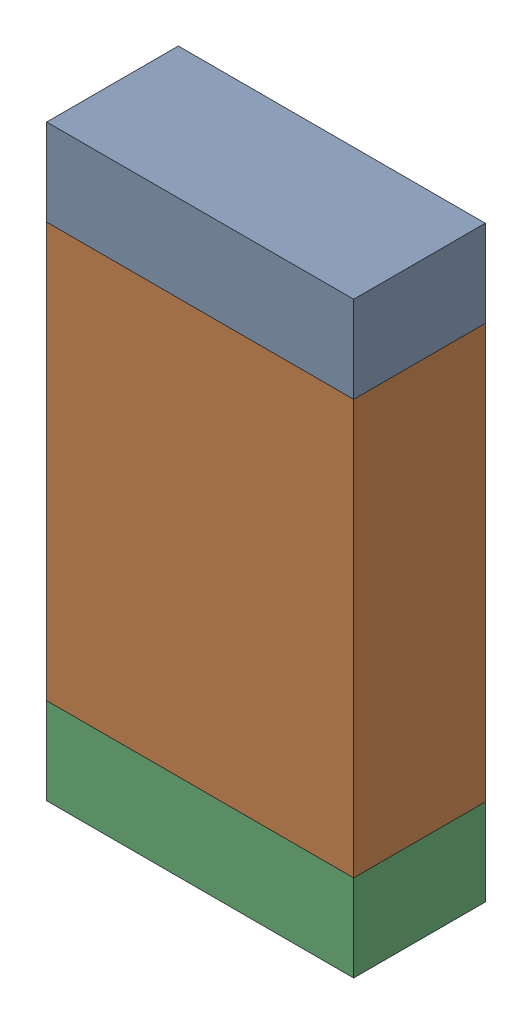
SolidWorks assembly R02, configuration Default. Lengths in mm.
Overall size (1.75 3.35 0.75).
6 component instances, 2 part files, 0 mates.
Components (placement in the parent):
- 959207032-1: 959207032 [Default] at (128.1431 81.3844 0) size (1.75 0.49 0.75)
  - Extruded-4-1: Extruded-4 [Default] at origin size (1.75 0.49 0.75)
- 959207168-1: 959207168 [Default] at (128.1431 79.9569 0) size (1.75 2.36 0.75)
  - Extruded-5-1: Extruded-5 [Default] at origin size (1.75 2.36 0.75)
- 959207032-2: 959207032 [Default] at (128.1431 78.5294 0) size (1.75 0.49 0.75)
  - Extruded-4-1: Extruded-4 [Default] at origin size (1.75 0.49 0.75)
